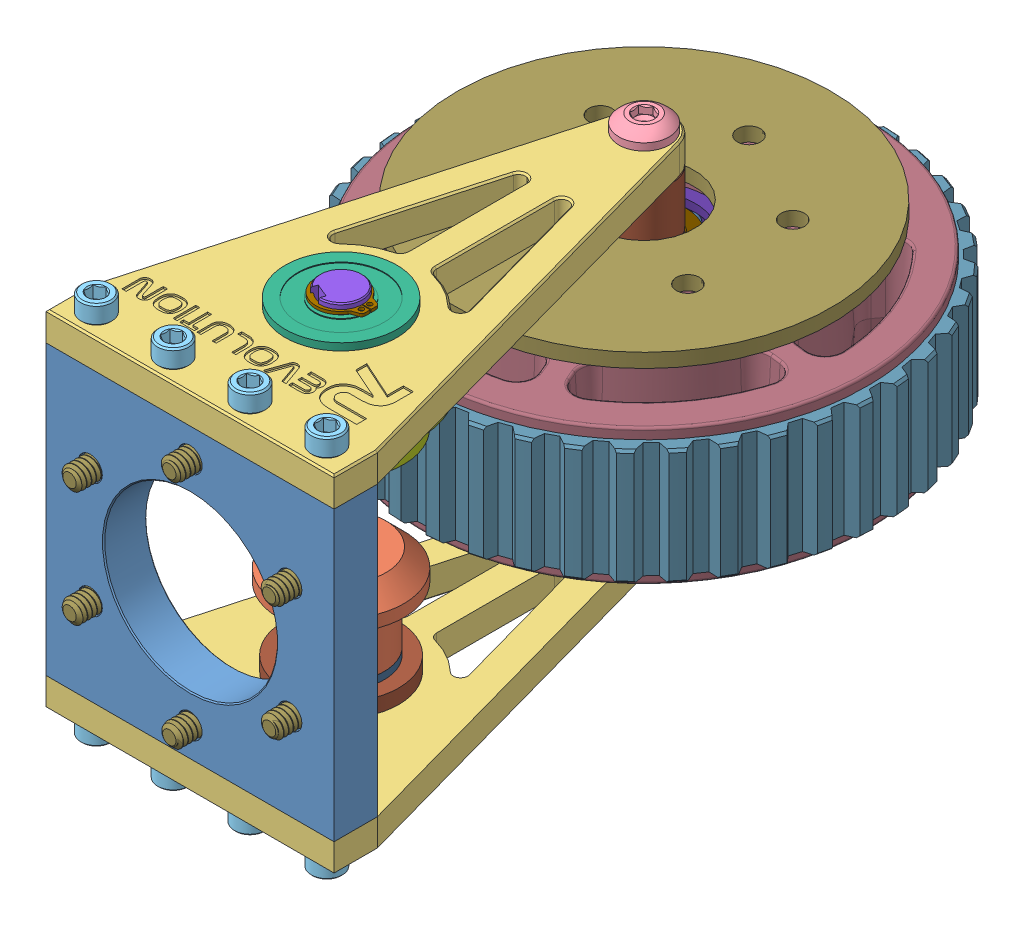
SolidWorks assembly cs_wheel_box_asm_plaction, configuration Default. Lengths in mm.
Overall size (149.25 84.94 179.3).
75 component instances, 30 part files, 0 mates.
Components (placement in the parent):
- revo2_wheel_box_cap-1: revo2_wheel_box_cap [Default] at origin size (63.5 63.5 9.53)
- 6843K12_miter_gear_1-1: 6843K12_miter_gear_1 [Default] at (1.3308 15.2099 -25.4535) x (-0.668029 0 0.744136) z (0.744136 0 0.668029) size (27.69 19.05 27.69)
- revo2_side_plate-1: revo2_side_plate [Default] at (-18.57 61.2601 -1.4632) x (1 0 0) z (0 -1 0) size (63.5 106.45 6.35)
- revo2_side_plate-2: revo2_side_plate [Default] at (18.217 -14.9399 -1.4632) x (-1 0 0) z (0 1 0) size (63.5 106.45 6.35)
- BHCS_91255A535-1: BHCS_91255A535 [Default] at (-0.1765 -14.9399 -90.5764) x (1 0 0) z (0 -1 0) size (11.23 11.23 13.63)
- 91251A192_shcs-1: 91251A192_shcs [Default] at (-25.5765 51.7351 4.7625) x (1 0 0) z (0 -1 0) size (6.86 6.86 13.9)
- 91251A192_shcs-2: 91251A192_shcs [Default] at (25.2235 51.7351 4.7625) x (1 0 0) z (0 -1 0) size (6.86 6.86 13.9)
- 91251A192_shcs-3: 91251A192_shcs [Default] at (-8.6423 51.7351 4.7665) x (1 0 0) z (0 -1 0) size (6.86 6.86 13.9)
- 91251A192_shcs-4: 91251A192_shcs [Default] at (8.2893 -5.4149 4.7665) x (1 0 0) z (0 1 0) size (6.86 6.86 13.9)
- 91251A192_shcs-5: 91251A192_shcs [Default] at (-25.5765 -5.4149 4.7625) x (1 0 0) z (0 1 0) size (6.86 6.86 13.9)
- 91251A192_shcs-6: 91251A192_shcs [Default] at (25.2235 -5.4149 4.7625) x (1 0 0) z (0 1 0) size (6.86 6.86 13.9)
- brf-06_1-1: brf-06_1 [Default] at (-0.1765 59.2789 -23.7744) x (1 0 0) z (0 1 0) size (24.59 24.59 7.11)
- brf-06_1-2: brf-06_1 [Default] at (-0.1765 -12.9587 -23.7744) x (0.755419 0 -0.655243) z (0 -1 0) size (24.59 24.59 7.11)
- 16t_ws_globe_gear-1: 16t_ws_globe_gear [Default] at (2.3218 39.2687 -25.5275) x (0.818565 0 -0.574414) z (0.574414 0 0.818565) size (35.31 10.29 35.31)
- revo2_cross_drive_shaft-1: revo2_cross_drive_shaft [Default] at (136.4364 723.0009 -354.9485) x (0 -1 0) z (-0.924435 0 -0.381339) size (83.39 9.26 9.53)
- Imported_1-1: Imported_1 [Default] at (-0.1765 -16.9719 -23.7744) x (0 1 0) z (0 0 1) size (0.64 12.09 10.6)
- Imported_1-2: Imported_1 [Default] at (-0.1765 63.4318 -23.7744) x (0 -1 0) z (0 0 1) size (0.64 12.09 10.6)
- large_thrust_bushing_1-1: large_thrust_bushing_1 [Default] at (-0.1765 -5.4149 -23.7744) x (1 0 0) z (0 1 0) size (19.05 19.05 1.57)
- 91251A192_shcs-7: 91251A192_shcs [Default] at (8.2893 51.7351 4.7645) x (1 0 0) z (0 -1 0) size (6.86 6.86 13.9)
- 91251A192_shcs-8: 91251A192_shcs [Default] at (-8.6423 -5.4149 4.7645) x (1 0 0) z (0 1 0) size (6.86 6.86 13.9)
- Imported_1-3: Imported_1 [Default] at (-0.1765 15.6544 -23.7744) x (0 -1 0) z (0 0 1) size (0.64 12.09 10.6)
- Imported_1-4: Imported_1 [Default] at (-0.1765 48.5474 -23.7744) x (0 -1 0) z (0 0 1) size (0.64 12.09 10.6)
- Imported_1-5: Imported_1 [Default] at (-0.1765 37.3714 -23.7744) x (0 1 0) z (0 0 1) size (0.64 12.09 10.6)
- BHCS_91255A535-2: BHCS_91255A535 [Default] at (-0.1765 61.2601 -90.5764) x (0.396029 0 -0.918238) z (0 1 0) size (11.23 11.23 13.63)
- revo2_wheel_shaft-1: revo2_wheel_shaft [Default] at (-0.1765 -8.5899 -90.5764) x (0.571408 0 0.820666) z (0 1 0) size (12.7 12.7 63.5)
- AM_36t_sprocket-1: AM_36t_sprocket [Default] at (-0.1765 48.1029 -90.5764) x (0.524782 0 0.851237) z (0 -1 0) size (82.55 82.55 3.1)
- 4Plaction-500bearing-1: 4Plaction-500bearing [Default] at (-0.1765 3.3481 -90.5764) x (0 1 0) z (-0.599972 0 0.800021) size (41.66 115.7 115.7)
  - 4MW_d011-1: 4MW_d011 [Default] at origin size (22.87 98.05 98.05)
  - 4MW_d011-2: 4MW_d011 [Default] at (41.656 0 0) x (-1 0 0) z (0 0 -1) size (22.87 98.05 98.05)
  - 4RoughTread1-1: 4RoughTread1 [Default] at (8.128 0 0) x (0 -0.992815 0.119662) z (1 0 0) size (104 104 25.4)
  - 10-32_nylock_nut1-1: 10-32_nylock_nut1 [Default] at (130.8703 19.4882 -76.5177) x (0 -0.340837 0.940122) z (-1 0 0) size (11.68 10.93 7.15)
  - 10-32_nylock_nut1-2: 10-32_nylock_nut1 [Default] at (130.8703 76.0104 -21.3816) x (0 -0.984588 0.174888) z (-1 0 0) size (11.68 10.93 7.15)
  - 10-32_nylock_nut1-3: 10-32_nylock_nut1 [Default] at (130.8703 56.5222 55.1361) x (0 -0.643751 -0.765235) z (-1 0 0) size (11.68 10.93 7.15)
  - 10-32_nylock_nut1-4: 10-32_nylock_nut1 [Default] at (130.8703 -19.4882 76.5177) x (0 0.340837 -0.940122) z (-1 0 0) size (11.68 10.93 7.15)
  - 10-32_nylock_nut1-5: 10-32_nylock_nut1 [Default] at (130.8703 -76.0104 21.3816) x (0 0.984588 -0.174888) z (-1 0 0) size (11.68 10.93 7.15)
  - 10-32_nylock_nut1-6: 10-32_nylock_nut1 [Default] at (130.8703 -56.5222 -55.1361) x (0 0.643751 0.765235) z (-1 0 0) size (11.68 10.93 7.15)
  - 10-32x1375_shcs1-1: 10-32x1375_shcs1 [Default] at (1.5748 0 23.8125) x (0 -0.961068 -0.276312) z (0 0.276312 -0.961068) size (7.82 39.7 7.82)
  - 10-32x1375_shcs1-2: 10-32x1375_shcs1 [Default] at (1.5748 -20.6222 11.9062) x (0 -0.241241 -0.970465) z (0 0.970465 -0.241241) size (7.82 39.7 7.82)
  - 10-32x1375_shcs1-3: 10-32x1375_shcs1 [Default] at (1.5748 -20.6222 -11.9062) x (0 0.719827 -0.694154) z (0 0.694154 0.719827) size (7.82 39.7 7.82)
  - 10-32x1375_shcs1-4: 10-32x1375_shcs1 [Default] at (1.5748 0 -23.8125) x (0 0.961068 0.276312) z (0 -0.276312 0.961068) size (7.82 39.7 7.82)
  - 10-32x1375_shcs1-5: 10-32x1375_shcs1 [Default] at (1.5748 20.6222 -11.9062) x (0 0.241241 0.970465) z (0 -0.970465 0.241241) size (7.82 39.7 7.82)
  - 10-32x1375_shcs1-6: 10-32x1375_shcs1 [Default] at (1.5748 20.6222 11.9062) x (0 -0.719827 0.694154) z (0 -0.694154 -0.719827) size (7.82 39.7 7.82)
- ball_bearing_60355K150-1: ball_bearing_60355K150 [Default] at (-0.1765 38.5271 -90.5764) x (1 0 0) z (0 1 0) size (28.57 28.57 6.35)
  - NONE-1: NONE [Default] at origin size (28.57 28.57 6.35)
  - NONEA-1: NONEA [Default] at origin size (18.68 18.68 6.35)
  - NONEB-1: NONEB [Default] at origin size (3.43 3.43 3.43)
  - NONEC-1: NONEC [Default] at origin size (3.43 3.43 3.43)
  - NONED-1: NONED [Default] at origin size (3.43 3.43 3.43)
  - NONEE-1: NONEE [Default] at origin size (3.43 3.43 3.43)
  - NONEF-1: NONEF [Default] at origin size (3.43 3.43 3.43)
  - NONEG-1: NONEG [Default] at origin size (3.43 3.43 3.43)
  - NONEH-1: NONEH [Default] at origin size (3.43 3.43 3.43)
  - NONEI-1: NONEI [Default] at origin size (3.43 3.43 3.43)
  - NONEJ-1: NONEJ [Default] at origin size (3.43 3.43 3.43)
  - NONEK-1: NONEK [Default] at origin size (3.43 3.43 3.43)
- ball_bearing_60355K150-2: ball_bearing_60355K150 [Default] at (-0.1765 9.8251 -90.5764) x (1 0 0) z (0 1 0) size (28.57 28.57 6.35)
  - NONE-1: NONE [Default] at origin size (28.57 28.57 6.35)
  - NONEA-1: NONEA [Default] at origin size (18.68 18.68 6.35)
  - NONEB-1: NONEB [Default] at origin size (3.43 3.43 3.43)
  - NONEC-1: NONEC [Default] at origin size (3.43 3.43 3.43)
  - NONED-1: NONED [Default] at origin size (3.43 3.43 3.43)
  - NONEE-1: NONEE [Default] at origin size (3.43 3.43 3.43)
  - NONEF-1: NONEF [Default] at origin size (3.43 3.43 3.43)
  - NONEG-1: NONEG [Default] at origin size (3.43 3.43 3.43)
  - NONEH-1: NONEH [Default] at origin size (3.43 3.43 3.43)
  - NONEI-1: NONEI [Default] at origin size (3.43 3.43 3.43)
  - NONEJ-1: NONEJ [Default] at origin size (3.43 3.43 3.43)
  - NONEK-1: NONEK [Default] at origin size (3.43 3.43 3.43)
- bushing_backer_1-1: bushing_backer_1 [Default] at (-0.1765 -5.4149 -23.7744) x (1 0 0) z (0 -1 0) size (25.4 25.4 3.17)
- 90128A218-1: 90128A218 [Default] at (-22.1736 35.8601 14.097) size (7.92 7.92 14.58)
- 90128A218-2: 90128A218 [Default] at (-22.1736 10.4601 14.097) x (0.5 0.866025 0) z (0 0 1) size (7.92 7.92 14.58)
- 90128A218-3: 90128A218 [Default] at (-0.1765 -2.2399 14.097) x (-0.5 0.866025 0) z (0 0 1) size (7.92 7.92 14.58)
- 90128A218-4: 90128A218 [Default] at (21.8205 10.4601 14.097) x (-1 0 0) z (0 0 1) size (7.92 7.92 14.58)
- 90128A218-5: 90128A218 [Default] at (21.8205 35.8601 14.097) x (-0.5 -0.866025 0) z (0 0 1) size (7.92 7.92 14.58)
- 90128A218-6: 90128A218 [Default] at (-0.1765 48.5601 14.097) x (0.5 -0.866025 0) z (0 0 1) size (7.92 7.92 14.58)
